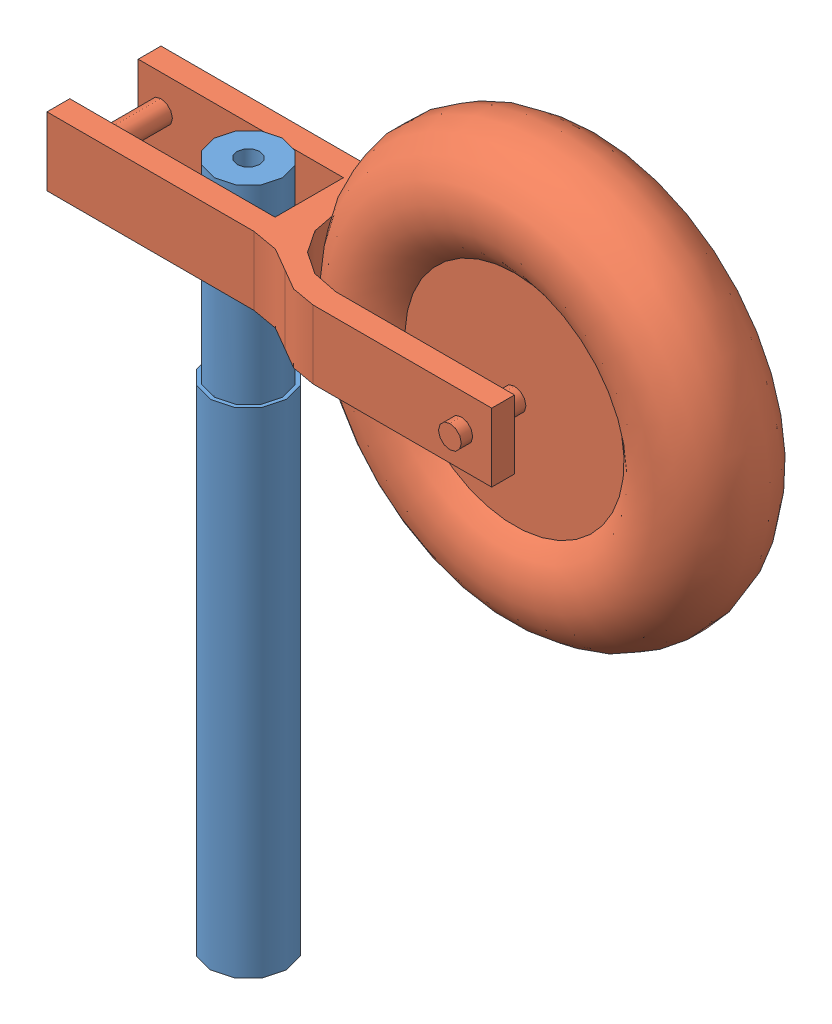
SolidWorks assembly front landing gear, configuration Default. Lengths in mm.
Overall size (86.5 112.5 27).
2 component instances, 2 part files, 9 mates.
Components (placement in the parent):
- landing gear main rod-1: landing gear main rod [Default] at (-37.2246 -38.7177 15.3748) size (10 90 10)
- wheel-1: wheel [Default] at (-29.2246 41.7823 15.3748) x (0 0 -1) z (0 1 0) size (27 86.5 55)
Mates (geometry in assembly coordinates):
- Concentric1: concentric: cylinder of landing gear main rod-1 through (-37.2246 46.2823 -17.1252) axis (0 0 1) radius 1.5; cylinder of wheel-1 through (-37.2246 46.2823 27.1174) axis (0 0 -1) radius 1.5
- Width1: width: plane of wheel-1 through (-56.2246 50.7823 19.8748) normal (0 0 -1); plane of wheel-1 through (-56.2246 50.7823 10.8748) normal (0 0 1); axis of landing gear main rod-1 through (-37.2246 51.2823 15.3748) axis (0 -1 0)
- Parallel1: parallel anti-aligned: plane of landing gear main rod-1 through (-37.2246 51.2823 15.3748) normal (0 1 0); plane of wheel-1 through (-29.0027 41.7823 32.8748) normal (0 -1 0)
- Concentric2: concentric: cylinder of landing gear main rod-1 through (-37.2246 26.2823 15.3748) axis (0 -1 0) radius 5; cylinder of Side Gear suport-1 through (-37.2246 -92.8251 15.3748) axis (0 1 0) radius 5
- Parallel2: parallel: plane of wheel-1 through (-56.2246 50.7823 22.8748) normal (0 0 1); plane of Side Gear suport-1 through (-36.5798 -62.8251 35.0465) normal (0 0 1)
- Coincident3: coincident anti-aligned: plane of landing gear main rod-1 through (-37.2246 -38.7177 15.3748) normal (0 -1 0); plane of Side Gear suport-1 through (-37.2246 -38.7177 15.3748) normal (0 1 0)
- Concentric3: concentric anti-aligned: cylinder of landing gear main rod-1 through (-37.2246 26.2823 15.3748) axis (0 -1 0) radius 5; cylinder of Front gear support-1 through (-37.2246 -38.7177 15.3748) axis (0 1 0) radius 5
- Parallel3: parallel aligned: plane of wheel-1 through (-56.2246 50.7823 22.8748) normal (0 0 1); plane of Front gear support-1 through (-212.1402 -8.7167 34.7977) normal (0 0 1)
- Coincident5: coincident anti-aligned: plane of landing gear main rod-1 through (-37.2246 -38.7177 15.3748) normal (0 -1 0); plane of Front gear support-1 through (-37.2246 -38.7177 15.3748) normal (0 1 0)
